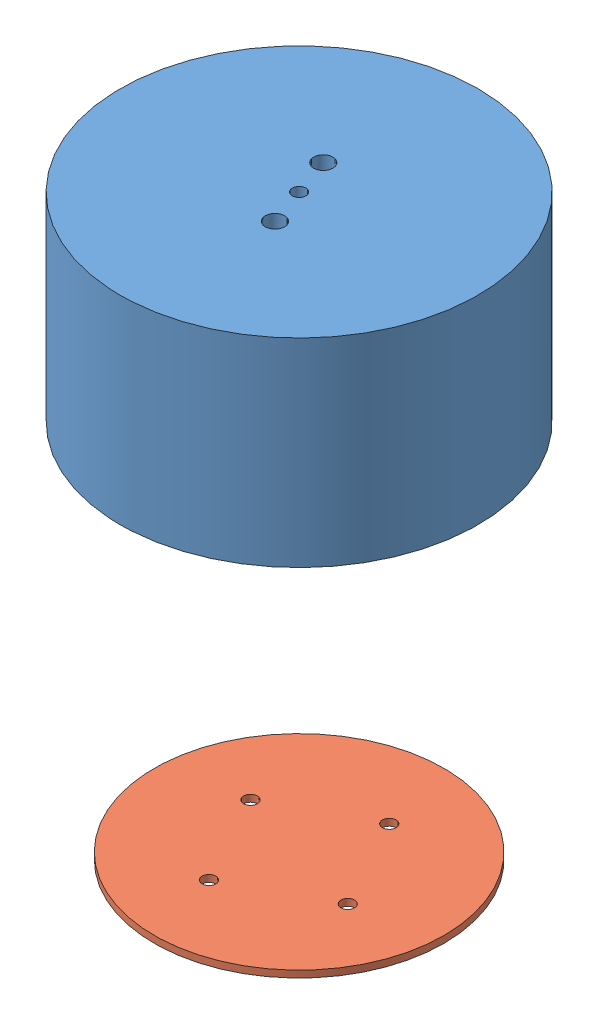
SolidWorks assembly PlateAssembly, configuration Default. Lengths in mm.
Overall size (63.48 101.82 63.48).
2 component instances, 2 part files, 2 mates.
Components (placement in the parent):
- PlateSleeve-2: PlateSleeve [Default] at (8.672 12.3005 62.9796) size (63 35 63)
- Plate-1: Plate [Default] at (8.672 -53.3079 62.9796) x (-0.286593 0 0.958052) z (-0.958052 0 -0.286593) size (51 1.21 51)
Mates (geometry in assembly coordinates):
- Coincident3: coincident: line of PlateSleeve-2 through (8.672 47.3005 62.9796) axis (0 -1 0); point of Plate-1
- Parallel1: parallel anti-aligned: plane of PlateSleeve-2 through (8.672 40.3005 62.9796) normal (0 -1 0); plane of Plate-1 through (8.672 -53.3079 62.9796) normal (0 1 0)
